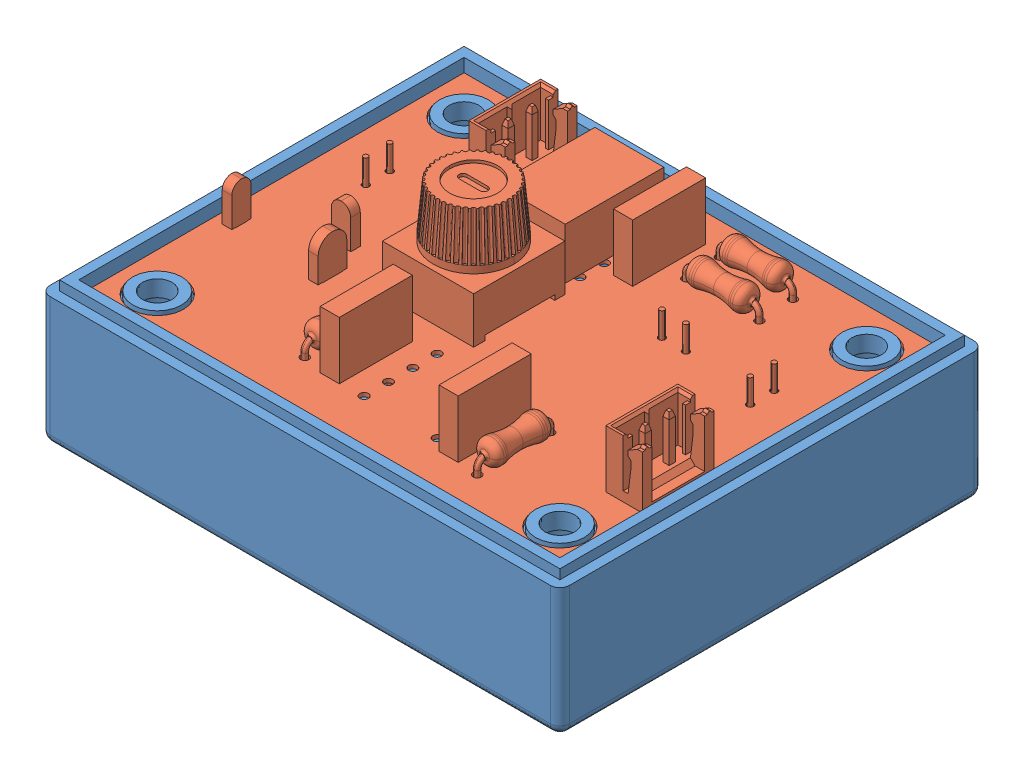
SolidWorks assembly ASSEMBLAGE_PCB_BAS, configuration Défaut. Lengths in mm.
Overall size (55.14 23.62 44.2).
2 component instances, 2 part files, 3 mates.
Components (placement in the parent):
- piècebas-1: piècebas [Défaut] at (-85.7489 16.2493 5.2569) size (54.2 14.5 44.2)
- carte_pcb.step-2: carte_pcb.step [Défaut] at (-108.7074 29.4608 19.9) x (1 0 0) z (0 1 0) size (53.04 40 22.42)
Mates (geometry in assembly coordinates):
- Coaxiale10: concentric anti-aligned: circle of carte_pcb.step-2; circle of piècebas-1
- Coaxiale11: concentric anti-aligned: circle of piècebas-1; circle of carte_pcb.step-2
- Coïncidente12: coincident anti-aligned: plane of piècebas-1 through (-61.1574 29.0493 15.9) normal (0 1 0); plane of carte_pcb.step-2 through (-83.7074 29.0493 -0.1) normal (0 -1 0)
